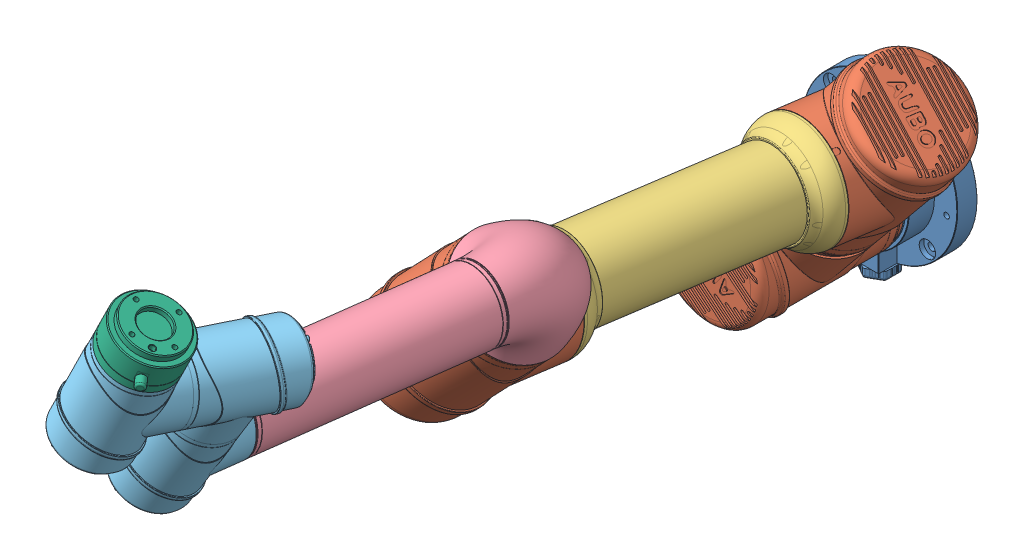
SolidWorks assembly i5-V2, configuration Default. Lengths in mm.
Overall size (329.36 556.57 1276.43).
10 component instances, 6 part files, 18 mates.
Components (placement in the parent):
- ID-5-00-1: ID-5-00 [默认] at (22.1001 -15.8005 171.3348) size (170 182.63 50)
- ID-25-1: ID-25 [默认] at (22.1001 -15.8005 216.8345) x (-0.773035 0.634364 0) z (0.634364 0.773035 0) size (122.57 165.79 130)
- ID-25-2: ID-25 [默认] at (76.9724 51.0667 277.8345) x (0.769172 -0.631195 0.099836) z (-0.077177 0.063333 0.995004) size (122.57 165.79 130)
- 100_1_1_1-1: 100_1_1_1 [默认] at (133.1867 258.835 778.0131) x (-0.911981 0.398811 -0.096122) z (-0.077177 0.063333 0.995004) size (116 116 284)
- ID-25-3: ID-25 [默认] at (126.3254 168.159 684.2582) x (0.718818 -0.688034 0.099549) z (0.077177 -0.063333 -0.995004) size (122.57 165.79 130)
- 70_1_1_1-1: 70_1_1_1 [默认] at (215.7225 197.9733 180.2925) x (0.719739 -0.688782 0.086925) z (0.068057 -0.054604 -0.996186) size (122.26 89.09 394.83)
- ID-14-1: ID-14 [默认] at (165.373 270.0303 1058.6811) x (0.852133 -0.516127 0.086506) z (0.518882 0.85477 -0.011404) size (79.03 87.5 120.19)
- ID-14-2: ID-14 [默认] at (185.1796 326.7662 1100.1977) x (-0.82123 0.494728 -0.284299) z (-0.237368 0.156882 0.958668) size (79.03 87.5 120.19)
- ID-14-3: ID-14 [默认] at (190.1028 375.6683 1154.2276) x (0.872832 -0.398744 0.281368) z (0.426405 0.903544 -0.042283) size (79.03 87.5 120.19)
- i7ID7-1: i7ID7 [默认] at (210.0586 417.9542 1152.2487) x (-0.426405 -0.903544 0.042283) z (-0.664272 0.34453 0.663357) size (39.5 86.7 75)
Mates (geometry in assembly coordinates):
- 重合2: coincident: plane of ID-5-00-1 through (22.1001 -15.8005 199.3348) normal (0 0 1); plane of ID-25-1 through (22.1001 -15.8005 199.3348) normal (0 0 -1)
- 同心2: concentric: circle of ID-5-00-1; circle of ID-25-1
- 重合4: coincident: plane of ID-25-1 through (65.8712 37.5388 277.8345) normal (0.634364 0.773035 0); plane of ID-25-2 through (65.8712 37.5388 277.8345) normal (-0.634364 -0.773035 0)
- 同心3: concentric: circle of ID-25-1; circle of ID-25-2
- 同心4: concentric: circle of ID-25-2; circle of 100_1_1_1-1
- 重合6: coincident: plane of ID-25-2; plane of 100_1_1_1-1
- 重合7: coincident: plane of 100_1_1_1-1; plane of ID-25-3
- 同心5: concentric: cone of 100_1_1_1-1 through (318.4244 -68.1627 491.817) axis (0.598983 -0.491535 0.632149); circle of ID-25-3
- 重合9: coincident: plane of ID-25-3; plane of 70_1_1_1-1
- 同心7: concentric: circle of 70_1_1_1-1; circle of ID-14-1
- 重合11: coincident: plane of 70_1_1_1-1; plane of ID-14-1
- 重合12: coincident: plane of ID-14-1; plane of ID-14-2
- 同心9: concentric: circle of ID-14-1; circle of ID-14-2
- 重合18: coincident: plane of ID-14-2; plane of ID-14-3
- 同心10: concentric: circle of ID-14-2; circle of ID-14-3
- 重合20: coincident: plane of ID-14-3; plane of i7ID7-1
- 同心12: concentric: circle of ID-14-3; circle of i7ID7-1
- 同心13: concentric: circle of ID-25-3; circle of 70_1_1_1-1
